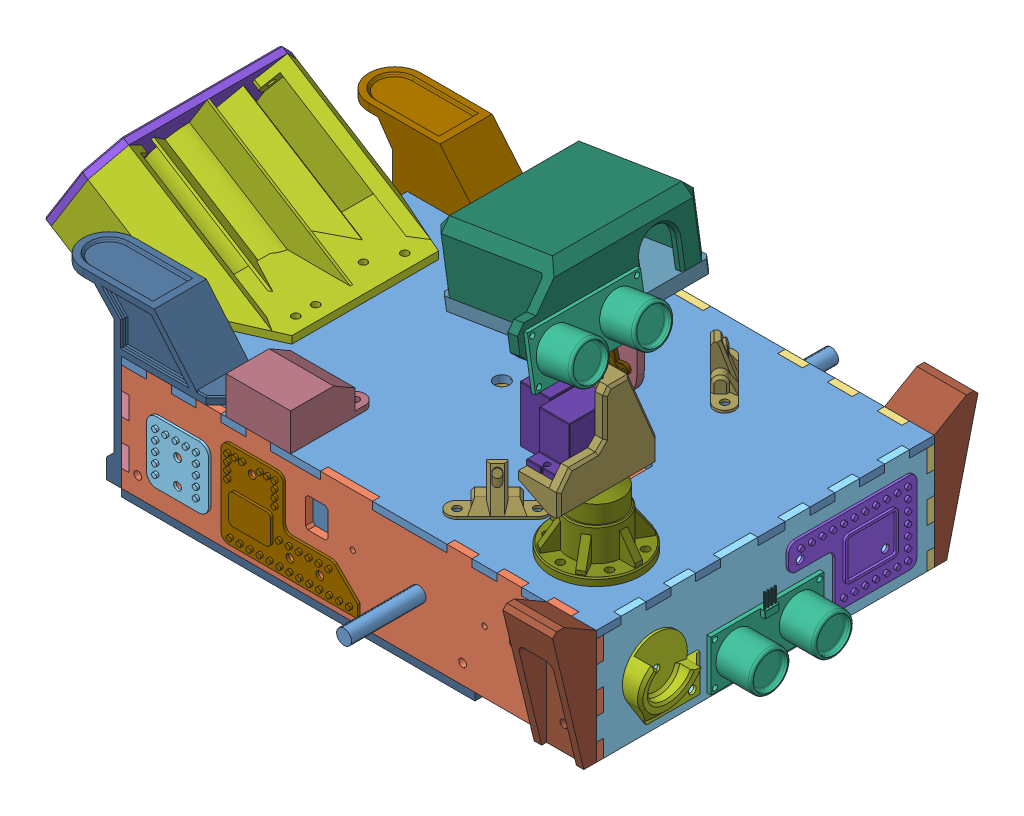
SolidWorks assembly bodySub-2, configuration Default. Lengths in mm.
Overall size (271.51 168.8 196).
99 component instances, 36 part files, 106 mates.
Components (placement in the parent):
- body-top-1: body-top [Default] at (-43.052 0 151.6865) x (1 0 0) z (0 1 0) size (191 136 3)
- body-right-1: body-right [Default] at (-43.052 -43 148.6865) size (191 46 3)
- body-left-1: body-left [Default] at (-43.052 -43 18.6865) x (-1 0 0) z (0 0 -1) size (191 46 3)
- body-rear-1: body-rear [Default] at (-43.052 -43 15.6865) x (0 0 -1) z (1 0 0) size (136 46 3)
- body-front-1: body-front [Default] at (147.948 -43 15.6865) x (0 0 1) z (-1 0 0) size (136 46 3)
- usSensor-1: usSensor [Default] at (-46.052 -45.75 62.8045) x (0 0 1) z (0 -1 0) size (45.5 15.6 26.2)
- usSensor-2: usSensor [Default] at (147.948 -20.8 61.6865) x (0 0 1) z (0 1 0) size (45.5 15.6 26.2)
- power-1: power [Default] at (-43.052 -43 151.6865) x (0 0 1) z (-1 0 0) size (84 85.03 90.67)
- powerCap-1: powerCap [Default] at (-74.8205 44.2822 15.6865) x (0 0 -1) z (-0.848048 0.529919 0) size (84 51.88 5)
- powerShoulder-left-1: powerShoulder-left [Default] at (-43.052 -43 15.6865) x (-1 0 0) z (0 0 -1) size (66.06 69 21)
- powerShoulder-right-1: powerShoulder-right [Default] at (-43.052 -43 109.6865) x (-1 0 0) z (0 0 -1) size (66.06 69 21)
- shoulder-1: shoulder [Default] at (127.948 -43 151.6865) size (20 53.5 17.6)
- shoulder-2: shoulder [Default] at (147.948 -43 15.6865) x (-1 0 0) z (0 0 -1) size (20 53.5 17.6)
- headSub-1: headSub [Default] at (131.8571 34.2972 110.6077) size (71.35 113.8 76.5) (flexible)
  - headServoMount-1: headServoMount [Default] at (-5.7591 24.2018 7.3288) x (0 0 1) z (1 0 0) size (39.75 36.12 28.6)
  - headMount-1: headMount [Default] at (-19.6139 25.1697 -5.5142) x (0.16009 -0.987102 0) z (0 0 -1) size (40 30 34)
  - headBaseplate-1: headBaseplate [Default] at (-50.728 44.8869 -23.5142) x (0 0 1) z (-0.987102 -0.16009 0) size (60 5 50)
  - headCanopy-1: headCanopy [Default] at (-6.1756 82.5045 -23.5142) x (0 0 1) z (0.16009 -0.987102 0) size (76.5 50 25)
  - usSensor-2: usSensor [Default] at (-0.5404 47.7585 50.4858) x (0 0 -1) z (0.16009 -0.987102 0) size (45.5 15.6 26.2)
  - mastMount-top-1: mastMount-top [Default] at (-11.9091 -31.2972 13.0788) size (36 28 36)
  - sg90Servo-1: sg90Servo [Default] at (-5.7591 24.0708 7.3288) x (0 0 1) z (1 0 0) size (32.7 29.37 12.3)
  - sg90Servo-2: sg90Servo [Default] at (-18.0591 24.5458 25.4538) x (0 -1 0) z (1 0 0) size (32.7 29.37 12.3)
  - sg90ServoHorn-star-1: sg90ServoHorn-star [Default] at (-27.3265 20.2151 -5.5142) x (0.16009 -0.987102 0) z (-0.987102 -0.16009 0) size (34.4 4 15.7)
  - pan slot head_am-1: pan slot head_am [B18.6.7M - M3 x 0.5 x 16 Slotted PHMS --16C] at (-20.6532 43.3822 5.4858) x (-0.16009 0.987102 0) z (0.259371 0.042065 -0.964861) size (18.4 5.6 5.6)
  - flat washer narrow_am-1: flat washer narrow_am [B18.22M - Plain washer, 3 mm, narrow] at (-22.6063 55.4248 5.4858) x (-0.16009 0.987102 0) z (-0.259371 -0.042065 0.964861) size (0.9 7 7)
  - flat washer narrow_am-2: flat washer narrow_am [B18.22M - Plain washer, 3 mm, narrow] at (-21.1815 46.6396 5.4858) x (-0.16009 0.987102 0) z (-0.259371 -0.042065 0.964861) size (0.9 7 7)
  - hex nut style 1_am-1: hex nut style 1_am [B18.2.4.1M - Hex nut, Style 1,  M3 x 0.5 --D-C] at (-22.9905 57.7939 5.4858) x (-0.259371 -0.042065 0.964861) z (-0.16009 0.987102 0) size (5.5 6.35 2.4)
  - pan slot head_am-2: pan slot head_am [B18.6.7M - M3 x 0.5 x 16 Slotted PHMS --16C] at (-20.6532 43.3822 18.4858) x (-0.16009 0.987102 0) z (0.259371 0.042065 -0.964861) size (18.4 5.6 5.6)
  - flat washer narrow_am-3: flat washer narrow_am [B18.22M - Plain washer, 3 mm, narrow] at (-22.6063 55.4248 18.4858) x (-0.16009 0.987102 0) z (-0.259371 -0.042065 0.964861) size (0.9 7 7)
  - flat washer narrow_am-4: flat washer narrow_am [B18.22M - Plain washer, 3 mm, narrow] at (-21.1815 46.6396 18.4858) x (-0.16009 0.987102 0) z (-0.259371 -0.042065 0.964861) size (0.9 7 7)
  - hex nut style 1_am-2: hex nut style 1_am [B18.2.4.1M - Hex nut, Style 1,  M3 x 0.5 --D-C] at (-22.9905 57.7939 18.4858) x (-0.259371 -0.042065 0.964861) z (-0.16009 0.987102 0) size (5.5 6.35 2.4)
  - pan slot head_am-3: pan slot head_am [B18.6.7M - M3 x 0.5 x 16 Slotted PHMS --16C] at (-31.4492 41.6313 18.4858) x (-0.16009 0.987102 0) z (0.259371 0.042065 -0.964861) size (18.4 5.6 5.6)
  - flat washer narrow_am-5: flat washer narrow_am [B18.22M - Plain washer, 3 mm, narrow] at (-33.4023 53.6739 18.4858) x (-0.16009 0.987102 0) z (-0.259371 -0.042065 0.964861) size (0.9 7 7)
  - flat washer narrow_am-6: flat washer narrow_am [B18.22M - Plain washer, 3 mm, narrow] at (-31.9775 44.8887 18.4858) x (-0.16009 0.987102 0) z (-0.259371 -0.042065 0.964861) size (0.9 7 7)
  - hex nut style 1_am-3: hex nut style 1_am [B18.2.4.1M - Hex nut, Style 1,  M3 x 0.5 --D-C] at (-33.7865 56.043 18.4858) x (-0.259371 -0.042065 0.964861) z (-0.16009 0.987102 0) size (5.5 6.35 2.4)
  - pan slot head_am-4: pan slot head_am [B18.6.7M - M3 x 0.5 x 16 Slotted PHMS --16C] at (-31.4492 41.6313 5.4858) x (-0.16009 0.987102 0) z (0.259371 0.042065 -0.964861) size (18.4 5.6 5.6)
  - flat washer narrow_am-7: flat washer narrow_am [B18.22M - Plain washer, 3 mm, narrow] at (-33.4023 53.6739 5.4858) x (-0.16009 0.987102 0) z (-0.259371 -0.042065 0.964861) size (0.9 7 7)
  - flat washer narrow_am-8: flat washer narrow_am [B18.22M - Plain washer, 3 mm, narrow] at (-31.9775 44.8887 5.4858) x (-0.16009 0.987102 0) z (-0.259371 -0.042065 0.964861) size (0.9 7 7)
  - hex nut style 1_am-4: hex nut style 1_am [B18.2.4.1M - Hex nut, Style 1,  M3 x 0.5 --D-C] at (-33.7865 56.043 5.4858) x (-0.259371 -0.042065 0.964861) z (-0.16009 0.987102 0) size (5.5 6.35 2.4)
  - pan slot head_am-5: pan slot head_am [B18.6.7M - M2 x 0.4 x 16 Slotted PHMS --16C] at (-24.2091 -0.9542 -2.2712) x (0 0 1) z (-0.877694 -0.479221 0) size (17.6 4 4)
  - flat washer narrow_am-9: flat washer narrow_am [B18.22M - Plain washer, 2 mm, narrow] at (-24.2091 -0.9542 0.2288) x (0 0 1) z (-0.877694 -0.479221 0) size (0.9 5 5)
  - flat washer narrow_am-10: flat washer narrow_am [B18.22M - Plain washer, 2 mm, narrow] at (-24.2091 -0.9542 10.7288) x (0 0 1) z (-0.877694 -0.479221 0) size (0.9 5 5)
  - hex nut style 1_am-5: hex nut style 1_am [B18.2.4.1M - Hex nut, Style 1,  M2 x 0.4 --D-C] at (-24.2091 -0.9542 12.3288) x (0.877694 0.479221 0) z (0 0 1) size (4 4.62 1.6)
  - pan slot head_am-7: pan slot head_am [B18.6.7M - M2 x 0.4 x 10 Slotted PHMS --10C] at (-24.2091 27.3458 4.8288) x (0 0 1) z (-0.99854 -0.054009 0) size (11.6 4 4)
  - flat washer narrow_am-13: flat washer narrow_am [B18.22M - Plain washer, 2 mm, narrow] at (-24.2091 27.3458 7.3288) x (0 0 1) z (-0.99854 -0.054009 0) size (0.9 5 5)
  - flat washer narrow_am-14: flat washer narrow_am [B18.22M - Plain washer, 2 mm, narrow] at (-24.2091 27.3458 13.7288) x (0 0 1) z (-0.99854 -0.054009 0) size (0.9 5 5)
  - hex nut style 1_am-7: hex nut style 1_am [B18.2.4.1M - Hex nut, Style 1,  M2 x 0.4 --D-C] at (-24.2091 27.3458 15.3288) x (0.99854 0.054009 0) z (0 0 1) size (4 4.62 1.6)
  - pan slot head_am-8: pan slot head_am [B18.6.7M - M2 x 0.4 x 10 Slotted PHMS --10C] at (-11.9091 10.9458 32.8288) x (0 -1 0) z (-0.98388 0 -0.178829) size (11.6 4 4)
  - flat washer narrow_am-15: flat washer narrow_am [B18.22M - Plain washer, 2 mm, narrow] at (-11.9091 8.4458 32.8288) x (0 -1 0) z (-0.98388 0 -0.178829) size (0.9 5 5)
  - flat washer narrow_am-16: flat washer narrow_am [B18.22M - Plain washer, 2 mm, narrow] at (-11.9091 2.0458 32.8288) x (0 -1 0) z (-0.98388 0 -0.178829) size (0.9 5 5)
  - hex nut style 1_am-8: hex nut style 1_am [B18.2.4.1M - Hex nut, Style 1,  M2 x 0.4 --D-C] at (-11.9091 0.4458 32.8288) x (0.98388 0 0.178829) z (0 -1 0) size (4 4.62 1.6)
  - pan slot head_am-9: pan slot head_am [B18.6.7M - M2 x 0.4 x 16 Slotted PHMS --16C] at (-11.9091 -5.6542 4.5288) x (0 1 0) z (-0.921484 0 -0.388417) size (17.6 4 4)
  - flat washer narrow_am-17: flat washer narrow_am [B18.22M - Plain washer, 2 mm, narrow] at (-11.9091 -3.1542 4.5288) x (0 1 0) z (-0.921484 0 -0.388417) size (0.9 5 5)
  - flat washer narrow_am-18: flat washer narrow_am [B18.22M - Plain washer, 2 mm, narrow] at (-11.9091 9.3458 4.5288) x (0 1 0) z (-0.970412 0 0.241457) size (0.9 5 5)
  - hex nut style 1_am-9: hex nut style 1_am [B18.2.4.1M - Hex nut, Style 1,  M2 x 0.4 --D-C] at (-11.9091 10.9458 4.5288) x (0.921484 0 0.388417) z (0 1 0) size (4 4.62 1.6)
  - flat washer narrow_am-19: flat washer narrow_am [B18.22M - Plain washer, 2 mm, narrow] at (-26.6104 33.6024 -4.0542) x (0 0 -1) z (0.283495 -0.958974 0) size (0.9 5 5)
  - flat washer narrow_am-20: flat washer narrow_am [B18.22M - Plain washer, 2 mm, narrow] at (-26.6104 33.6024 -10.4142) x (0 0 -1) z (0.283495 -0.958974 0) size (0.9 5 5)
  - hex nut style 1_am-10: hex nut style 1_am [B18.2.4.1M - Hex nut, Style 1,  M2 x 0.4 --D-C] at (-26.6104 33.6024 -12.0142) x (-0.283495 0.958974 0) z (0 0 -1) size (4 4.62 1.6)
  - pan slot head_am-10: pan slot head_am [B18.6.7M - M2 x 0.4 x 10 Slotted PHMS --10C] at (-26.6104 33.6024 -1.5542) x (0 0 -1) z (0.283495 -0.958974 0) size (11.6 4 4)
  - flat washer narrow_am-21: flat washer narrow_am [B18.22M - Plain washer, 2 mm, narrow] at (-18.1877 19.7724 -4.0542) x (0 0 -1) z (0.283495 -0.958974 0) size (0.9 5 5)
  - flat washer narrow_am-22: flat washer narrow_am [B18.22M - Plain washer, 2 mm, narrow] at (-18.1877 19.7724 -10.4142) x (0 0 -1) z (0.283495 -0.958974 0) size (0.9 5 5)
  - hex nut style 1_am-11: hex nut style 1_am [B18.2.4.1M - Hex nut, Style 1,  M2 x 0.4 --D-C] at (-18.1877 19.7724 -12.0142) x (-0.283495 0.958974 0) z (0 0 -1) size (4 4.62 1.6)
  - pan slot head_am-11: pan slot head_am [B18.6.7M - M2 x 0.4 x 10 Slotted PHMS --10C] at (-18.1877 19.7724 -1.5542) x (0 0 -1) z (0.283495 -0.958974 0) size (11.6 4 4)
  - flat washer narrow_am-23: flat washer narrow_am [B18.22M - Plain washer, 2 mm, narrow] at (-23.1685 12.3797 -4.0542) x (0 0 -1) z (0.283495 -0.958974 0) size (0.9 5 5)
  - flat washer narrow_am-24: flat washer narrow_am [B18.22M - Plain washer, 2 mm, narrow] at (-23.1685 12.3797 -10.4142) x (0 0 -1) z (0.283495 -0.958974 0) size (0.9 5 5)
  - hex nut style 1_am-12: hex nut style 1_am [B18.2.4.1M - Hex nut, Style 1,  M2 x 0.4 --D-C] at (-23.1685 12.3797 -12.0142) x (-0.283495 0.958974 0) z (0 0 -1) size (4 4.62 1.6)
  - pan slot head_am-12: pan slot head_am [B18.6.7M - M2 x 0.4 x 10 Slotted PHMS --10C] at (-23.1685 12.3797 -1.5542) x (0 0 -1) z (0.283495 -0.958974 0) size (11.6 4 4)
  - flat washer narrow_am-25: flat washer narrow_am [B18.22M - Plain washer, 2 mm, narrow] at (-30.2304 17.8193 -4.0542) x (0 0 -1) z (0.283495 -0.958974 0) size (0.9 5 5)
  - flat washer narrow_am-26: flat washer narrow_am [B18.22M - Plain washer, 2 mm, narrow] at (-30.2304 17.8193 -10.4142) x (0 0 -1) z (0.283495 -0.958974 0) size (0.9 5 5)
  - hex nut style 1_am-13: hex nut style 1_am [B18.2.4.1M - Hex nut, Style 1,  M2 x 0.4 --D-C] at (-30.2304 17.8193 -12.0142) x (-0.283495 0.958974 0) z (0 0 -1) size (4 4.62 1.6)
  - pan slot head_am-13: pan slot head_am [B18.6.7M - M2 x 0.4 x 10 Slotted PHMS --10C] at (-30.2304 17.8193 -1.5542) x (0 0 -1) z (0.283495 -0.958974 0) size (11.6 4 4)
  - flat washer narrow_am-27: flat washer narrow_am [B18.22M - Plain washer, 2 mm, narrow] at (-1.9228 66.276 6.6858) x (-0.987102 -0.16009 0) z (0.068011 -0.419347 0.905275) size (0.9 5 5)
  - flat washer narrow_am-28: flat washer narrow_am [B18.22M - Plain washer, 2 mm, narrow] at (-7.3518 65.3955 6.6858) x (-0.987102 -0.16009 0) z (0.068011 -0.419347 0.905275) size (0.9 5 5)
  - hex nut style 1_am-14: hex nut style 1_am [B18.2.4.1M - Hex nut, Style 1,  M2 x 0.4 --D-C] at (-8.9312 65.1394 6.6858) x (-0.068011 0.419347 -0.905275) z (-0.987102 -0.16009 0) size (4 4.62 1.6)
  - pan slot head_am-14: pan slot head_am [B18.6.7M - M2 x 0.4 x 10 Slotted PHMS --10C] at (0.545 66.6763 6.6858) x (-0.987102 -0.16009 0) z (0.068011 -0.419347 0.905275) size (11.6 4 4)
  - flat washer narrow_am-29: flat washer narrow_am [B18.22M - Plain washer, 2 mm, narrow] at (-1.9228 66.276 48.7858) x (-0.987102 -0.16009 0) z (0.068011 -0.419347 0.905275) size (0.9 5 5)
  - flat washer narrow_am-30: flat washer narrow_am [B18.22M - Plain washer, 2 mm, narrow] at (-8.3389 65.2354 48.7858) x (-0.987102 -0.16009 0) z (0.068011 -0.419347 0.905275) size (0.9 5 5)
  - hex nut style 1_am-15: hex nut style 1_am [B18.2.4.1M - Hex nut, Style 1,  M2 x 0.4 --D-C] at (-9.9183 64.9793 48.7858) x (-0.068011 0.419347 -0.905275) z (-0.987102 -0.16009 0) size (4 4.62 1.6)
  - pan slot head_am-15: pan slot head_am [B18.6.7M - M2 x 0.4 x 10 Slotted PHMS --10C] at (0.545 66.6763 48.7858) x (-0.987102 -0.16009 0) z (0.068011 -0.419347 0.905275) size (11.6 4 4)
- pivotAxle-1: pivotAxle [Default] at (76.448 -20 181.6865) x (-0.972905 0.231206 0) z (-0.231206 -0.972905 0) size (6 196 6)
- edison-arduino-1: edison-arduino [Default] at (-30.752 -13.38 66.6865) x (1 0 0) z (0 0 -1) size (127.2 12.67 72)
- diffMount-mid-1: diffMount-mid [Default] at (-43.052 0 151.6865) x (-1 0 0) z (0 -1 0) size (30 30 3)
- diffMount-bottom-1: diffMount-bottom [Default] at (-43.052 -3 151.6865) x (-1 0 0) z (0 -1 0) size (30 30 3)
- sideDetailA-left-1: sideDetailA-left [Default] at (-43.052 -43 15.6865) x (-1 0 0) z (0 0 -1) size (25 25 2)
- sideDetailB-1: sideDetailB [Default] at (-43.052 -43 15.6865) x (-1 0 0) z (0 0 -1) size (55 35 2)
- fontDetailA-1: fontDetailA [Default] at (147.948 -43 15.6865) x (0 0 -1) z (1 0 0) size (30.16 30.17 9.09)
- frontDetailB-1: frontDetailB [Default] at (147.948 -43 15.6865) x (0 0 -1) z (1 0 0) size (51.58 33 2)
- sideDetailB-mirr-1: sideDetailB-mirr [Default] at (-43.052 -43 151.6865) x (-1 0 0) z (0 0 -1) size (55 35 2)
- sideDetailA-left-2: sideDetailA-left [Default] at (3.948 -43 151.6865) size (25 25 2)
- bodyUnderCover-1: bodyUnderCover [Default] at (99.148 -43 15.6865) x (1 0 0) z (0 -1 0) size (142.2 136 9)
- underCoverMagnetMount-front-1: underCoverMagnetMount-front [Default] at (99.148 -43 15.6865) x (-1 0 0) z (0 1 0) size (7 7 11.3)
- underCoverMagnetMount-front-2: underCoverMagnetMount-front [Default] at (89.148 -43 151.6865) x (1 0 0) z (0 1 0) size (7 7 11.3)
- underCoverMagnetMount-front-3: underCoverMagnetMount-front [Default] at (-31.552 -43 15.6865) x (-1 0 0) z (0 1 0) size (7 7 11.3)
- underCoverMagnetMount-front-4: underCoverMagnetMount-front [Default] at (-41.552 -43 151.6865) x (1 0 0) z (0 1 0) size (7 7 11.3)
- topDetailA-1: topDetailA [Default] at (-43.052 3 151.6865) x (1 0 0) z (0 1 0) size (24.26 24.26 16)
- topDetailA-2: topDetailA [Default] at (108.7154 3 168.7548) x (0 0 -1) z (0 1 0) size (24.26 24.26 16)
- topDetailB-1: topDetailB [Default] at (-45.052 3 151.6865) x (1 0 0) z (0 1 0) size (26 34 15)
- topDetailCA-1: topDetailCA [Default] at (-46.5393 3 149.9052) x (1 0 0) z (0 1 0) size (20.56 18.54 22.66)
- topDetailCB-1: topDetailCB [Default] at (1.7026 61.1918 61.409) x (0.910046 -0.22774 0.34634) z (0.414508 0.5 -0.760384) size (46.65 24.53 4)
Mates (geometry in assembly coordinates):
- Coincident23: coincident anti-aligned: plane of body-front-1 through (147.948 -43 15.6865) normal (1 0 0); plane of usSensor-2 through (147.948 -20.8 61.6865) normal (-1 0 0)
- Coincident22: coincident anti-aligned: plane of body-top-1 through (144.948 -0.001 141.6865) normal (1 0 0); plane of body-front-1 through (144.948 -43 15.6865) normal (-1 0 0)
- Coincident21: coincident anti-aligned: plane of body-top-1 through (147.948 -0.001 141.6865) normal (0 0 -1); plane of body-front-1 through (147.949 -43 141.6865) normal (0 0 1)
- Coincident17: coincident anti-aligned: plane of body-top-1 through (-40.052 -0.001 35.6865) normal (-1 0 0); plane of body-rear-1 through (-40.052 -43 15.6865) normal (1 0 0)
- Coincident16: coincident anti-aligned: plane of body-top-1 through (-43.052 -0.001 25.6865) normal (0 0 1); plane of body-rear-1 through (-43.053 -43 25.6865) normal (0 0 -1)
- Coincident12: coincident anti-aligned: plane of body-top-1 through (-43.052 -0.001 18.6865) normal (0 0 -1); plane of body-left-1 through (-43.052 -43 18.6865) normal (0 0 1)
- Coincident11: coincident anti-aligned: plane of body-top-1 through (137.948 -0.001 15.6865) normal (-1 0 0); plane of body-left-1 through (137.948 3 15.6855) normal (1 0 0)
- Coincident7: coincident anti-aligned: plane of body-top-1 through (-43.052 -0.001 148.6865) normal (0 0 1); plane of body-right-1 through (-43.052 -43 148.6865) normal (0 0 -1)
- Coincident6: coincident anti-aligned: plane of body-top-1 through (-33.052 -0.001 151.6865) normal (1 0 0); plane of body-right-1 through (-33.052 0 151.6875) normal (-1 0 0)
- Coincident2: coincident anti-aligned: plane of body-top-1 through (-43.052 0 151.6865) normal (0 -1 0); plane of assembly through (0 0 0) normal (0 1 0)
- Coincident24: coincident anti-aligned: plane of power-1 through (-46.052 -43 151.6865) normal (-1 0 0); plane of usSensor-1 through (-46.052 -45.75 62.8045) normal (1 0 0)
- Concentric5: concentric anti-aligned: cylinder of body-top-1 through (-19.052 3 105.6173) axis (0 -1 0) radius 1.55; cylinder of power-1 through (-19.052 -43.001 105.6173) axis (0 1 0) radius 1.55
- Coincident25: coincident anti-aligned: plane of body-top-1 through (-43.052 3 151.6865) normal (0 1 0); plane of power-1 through (-13.052 3 151.6865) normal (0 -1 0)
- Concentric8: concentric aligned: cylinder of body-rear-1 through (-40.052 -27.05 63.6865) axis (-1 0 0) radius 1.05; cylinder of power-1 through (-40.0822 -27.05 63.6865) axis (-1 0 0) radius 1.05
- Coincident26: coincident anti-aligned: plane of power-1 through (-105.1238 -4.2132 151.6865) normal (-0.848048 0.529919 0); plane of powerCap-1 through (-74.8205 44.2822 15.6865) normal (0.848048 -0.529919 0)
- Concentric11: concentric anti-aligned: cylinder of powerCap-1 through (-83.4594 36.1202 56.0789) axis (0.848048 -0.529919 0) radius 1.55; cylinder of power-1 through (2.7341 -17.7395 56.0789) axis (-0.848048 0.529919 0) radius 1.55
- Concentric12: concentric anti-aligned: cylinder of power-1 through (2.7341 -17.7395 111.2941) axis (-0.848048 0.529919 0) radius 1.55; cylinder of powerCap-1 through (-83.4594 36.1202 111.2941) axis (0.848048 -0.529919 0) radius 1.55
- Coincident27: coincident anti-aligned: plane of body-rear-1 through (-43.052 -43 15.6865) normal (-1 0 0); plane of powerShoulder-right-1 through (-43.052 -43 151.6865) normal (1 0 0)
- Coincident28: coincident anti-aligned: plane of body-top-1 through (-43.052 3 151.6865) normal (0 1 0); plane of powerShoulder-right-1 through (-43.052 3 81.1263) normal (0 -1 0)
- Concentric13: concentric anti-aligned: cylinder of body-top-1 through (-8.052 3 135.6865) axis (0 -1 0) radius 1.55; cylinder of powerShoulder-right-1 through (-8.052 -43.001 135.6865) axis (0 1 0) radius 1.55
- Coincident29: coincident anti-aligned: plane of body-rear-1 through (-43.052 -43 15.6865) normal (-1 0 0); plane of powerShoulder-left-1 through (-43.052 -43 15.6865) normal (1 0 0)
- Coincident30: coincident anti-aligned: plane of body-top-1 through (-43.052 3 151.6865) normal (0 1 0); plane of powerShoulder-left-1 through (-43.052 3 86.2467) normal (0 -1 0)
- Concentric14: concentric anti-aligned: cylinder of body-top-1 through (-8.052 3 31.6865) axis (0 -1 0) radius 1.55; cylinder of powerShoulder-left-1 through (-8.052 -43.001 31.6865) axis (0 1 0) radius 1.55
- Coincident31: coincident anti-aligned: plane of body-left-1 through (-43.052 -43 15.6865) normal (0 0 -1); plane of shoulder-2 through (127.948 -43 15.6865) normal (0 0 1)
- Concentric15: concentric anti-aligned: cylinder of body-left-1 through (137.948 -13 15.6865) axis (0 0 1) radius 1.55; cylinder of shoulder-2 through (137.948 -13 12.6865) axis (0 0 -1) radius 1.55
- Concentric16: concentric anti-aligned: cylinder of body-left-1 through (137.948 -33 15.6865) axis (0 0 1) radius 1.55; cylinder of shoulder-2 through (137.948 -33 12.6865) axis (0 0 -1) radius 1.55
- Coincident32: coincident anti-aligned: plane of body-right-1 through (-43.052 -43 151.6865) normal (0 0 1); plane of shoulder-1 through (147.948 -43 151.6865) normal (0 0 -1)
- Concentric17: concentric anti-aligned: cylinder of body-right-1 through (137.948 -13 151.6865) axis (0 0 -1) radius 1.55; cylinder of shoulder-1 through (137.948 -13 154.6865) axis (0 0 1) radius 1.55
- Concentric18: concentric anti-aligned: cylinder of body-right-1 through (137.948 -33 151.6865) axis (0 0 -1) radius 1.55; cylinder of shoulder-1 through (137.948 -33 154.6865) axis (0 0 1) radius 1.55
- Coincident33: coincident anti-aligned: plane of body-top-1 through (-43.052 3 151.6865) normal (0 1 0); plane of headSub-1/mastMount-top-1 through (119.948 3 123.6865) normal (0 -1 0)
- Concentric19: concentric anti-aligned: cylinder of body-top-1 through (132.5054 3 116.4365) axis (0 -1 0) radius 1.55; cylinder of headSub-1/mastMount-top-1 through (132.5054 6 116.4365) axis (0 1 0) radius 1.55
- Concentric20: concentric anti-aligned: cylinder of body-top-1 through (107.3906 3 130.9365) axis (0 -1 0) radius 1.55; cylinder of headSub-1/mastMount-top-1 through (107.3906 6 130.9365) axis (0 1 0) radius 1.55
- Coincident34: coincident aligned: plane of body-top-1 through (-43.052 3 151.6865) normal (0 1 0); plane of body-front-1 through (144.948 3 151.6865) normal (0 1 0)
- Coincident35: coincident aligned: plane of body-top-1 through (-43.052 3 151.6865) normal (0 1 0); plane of body-left-1 through (-43.052 3 15.6865) normal (0 1 0)
- Coincident36: coincident aligned: plane of body-top-1 through (-43.052 3 151.6865) normal (0 1 0); plane of body-rear-1 through (-40.052 3 15.6865) normal (0 1 0)
- Coincident37: coincident aligned: plane of body-top-1 through (-43.052 3 151.6865) normal (0 1 0); plane of body-right-1 through (147.948 3 151.6865) normal (0 1 0)
- Concentric21: concentric anti-aligned: cylinder of body-left-1 through (76.448 -20 18.6875) axis (0 0 -1) radius 3; cylinder of pivotAxle-1 through (76.448 -20 -14.3135) axis (0 0 1) radius 3
- Symmetric2: symmetric aligned: plane of body-top-1 through (-43.052 0 83.6865) normal (0 0 -1); plane of pivotAxle-1 through (76.448 -20 -14.3135) normal (0 0 -1); plane of pivotAxle-1 through (76.448 -20 181.6865) normal (0 0 1)
- Parallel1: parallel anti-aligned: plane of body-top-1 through (-43.052 0 151.6865) normal (0 -1 0); plane of edison-arduino-1 through (-30.752 -13.38 66.6865) normal (0 1 0)
- Parallel2: parallel anti-aligned: plane of body-rear-1 through (-40.052 -43 15.6865) normal (1 0 0); plane of edison-arduino-1 through (-30.752 -15 66.6865) normal (-1 0 0)
- Distance2: distance = 2 mm anti-aligned: plane of edison-arduino-1 through (-30.752 -15 66.6865) normal (0 -1 0); cylinder of pivotAxle-1 through (76.448 -20 -14.3135) axis (0 0 1) radius 3
- Distance3: distance = 1 mm anti-aligned: plane of edison-arduino-1 through (80.448 -26 134.6865) normal (-1 0 0); cylinder of pivotAxle-1 through (76.448 -20 -14.3135) axis (0 0 1) radius 3
- Distance4: distance = 10 mm anti-aligned: plane of edison-arduino-1 through (-30.752 -15 138.6865) normal (0 0 1); plane of body-right-1 through (-43.052 -43 148.6865) normal (0 0 -1)
- InPlace1: in place: plane of body-top-1 through (-43.052 0 151.6865) normal (0 -1 0); plane of ? through (0 0 0) normal (0 -1 0); moOrthogonalPlaneRef_w of body-top-1 through (-43.052 0 151.6865) normal (0 -1 0); unknown of ?; plane of body-top-1 through (-43.052 0 151.6865) normal (0 -1 0); line of ? through (55 -55 0) axis (0 0 -1); plane of body-top-1 through (-43.052 0 151.6865) normal (0 -1 0); unknown of diffMount-mid-1
- Coincident41: coincident aligned: 
- Coincident42: coincident aligned: plane of body-top-1 through (-43.052 0 151.6865) normal (0 0 -1); unknown of diffMount-mid-1
- Coincident43: coincident anti-aligned: plane of body-top-1 through (-43.052 0 151.6865) normal (1 0 0); unknown of diffMount-mid-1
- InPlace2: in place: plane of diffMount-mid-1 through (41.948 -3 83.6865) normal (0 -1 0); plane of ? through (0 -3 0) normal (0 -1 0); plane of diffMount-mid-1 through (41.948 -3 83.6865) normal (0 -1 0); unknown of ?; plane of diffMount-mid-1 through (41.948 -3 83.6865) normal (0 -1 0); line of ? through (-55 0 -3) axis (0 -1 0); plane of diffMount-mid-1 through (41.948 -3 83.6865) normal (0 -1 0); unknown of diffMount-bottom-1
- Coincident44: coincident aligned: 
- Coincident45: coincident aligned: plane of diffMount-mid-1 through (-43.052 -3 151.6865) normal (0 0 -1); unknown of diffMount-bottom-1
- Coincident46: coincident anti-aligned: plane of diffMount-mid-1 through (-43.052 -3 151.6865) normal (1 0 0); unknown of diffMount-bottom-1
- InPlace3: in place: plane of body-left-1 through (-43.052 -43 15.6865) normal (0 0 -1); plane of ? through (0 0 15.6865) normal (0 0 -1); plane of body-left-1 through (-43.052 -43 15.6865) normal (0 0 -1); unknown of ?; plane of body-left-1 through (-43.052 -43 15.6865) normal (0 0 -1); plane of ? through (0 0 15.6865) normal (-1 0 0); plane of body-left-1 through (-43.052 -43 15.6865) normal (0 0 -1); unknown of ?
- Coincident47: coincident aligned: 
- Coincident48: coincident aligned: plane of body-left-1 through (-43.052 -43 15.6865) normal (0 1 0); unknown of ?
- Coincident49: coincident anti-aligned: plane of body-left-1 through (-43.052 -43 15.6865) normal (1 0 0); plane of ? through (-43.052 -43 15.6865) normal (-1 0 0)
- InPlace4: in place: plane of body-left-1 through (-43.052 -43 15.6865) normal (0 0 -1); plane of ? through (0 0 15.6865) normal (0 0 -1); plane of body-left-1 through (-43.052 -43 15.6865) normal (0 0 -1); unknown of ?; plane of body-left-1 through (-43.052 -43 15.6865) normal (0 0 -1); plane of ? through (0 0 15.6865) normal (-1 0 0); plane of body-left-1 through (-43.052 -43 15.6865) normal (0 0 -1); unknown of ?
- Coincident50: coincident aligned: 
- Coincident51: coincident aligned: plane of body-left-1 through (-43.052 -43 15.6865) normal (0 1 0); unknown of ?
- Coincident52: coincident anti-aligned: plane of body-left-1 through (-43.052 -43 15.6865) normal (1 0 0); plane of ? through (-43.052 -43 15.6865) normal (-1 0 0)
- InPlace5: in place: plane of body-front-1 through (147.948 -43 15.6865) normal (1 0 0); plane of ? through (147.948 0 0) normal (1 0 0); plane of body-front-1 through (147.948 -43 15.6865) normal (1 0 0); line of ? through (-55 147.948 0) axis (0 0 1); plane of body-front-1 through (147.948 -43 15.6865) normal (1 0 0); plane of ? through (147.948 0 0) normal (0 0 -1); plane of body-front-1 through (147.948 -43 15.6865) normal (1 0 0); unknown of ?
- Coincident53: coincident aligned: 
- Coincident54: coincident aligned: plane of body-front-1 through (147.948 -43 15.6865) normal (0 1 0); line of ? through (-43 15.6865 0) axis (1 0 0)
- Coincident55: coincident anti-aligned: plane of body-front-1 through (147.948 -43 15.6865) normal (0 0 1); plane of ? through (147.948 -43 15.6865) normal (0 0 -1)
- InPlace6: in place: plane of body-front-1 through (147.948 -43 15.6865) normal (1 0 0); plane of ? through (147.948 0 0) normal (1 0 0); plane of body-front-1 through (147.948 -43 15.6865) normal (1 0 0); line of ? through (-55 147.948 0) axis (0 0 1); plane of body-front-1 through (147.948 -43 15.6865) normal (1 0 0); plane of ? through (147.948 0 0) normal (0 0 -1); plane of body-front-1 through (147.948 -43 15.6865) normal (1 0 0); unknown of ?
- Coincident56: coincident aligned: 
- Coincident57: coincident aligned: plane of body-front-1 through (147.948 -43 15.6865) normal (0 1 0); line of ? through (-43 15.6865 0) axis (1 0 0)
- Coincident58: coincident anti-aligned: plane of body-front-1 through (147.948 -43 15.6865) normal (0 0 1); plane of ? through (147.948 -43 15.6865) normal (0 0 -1)
- Coincident59: coincident anti-aligned: plane of body-right-1 through (-43.052 -43 151.6865) normal (0 0 1); plane of sideDetailB-mirr-1 through (-43.052 -43 151.6865) normal (0 0 -1)
- Concentric22: concentric aligned: cylinder of body-right-1 through (10.448 -11 148.6855) axis (0 0 1) radius 1.55; cylinder of sideDetailB-mirr-1 through (10.448 -11 151.6855) axis (0 0 1) radius 1.55
- Concentric23: concentric aligned: cylinder of body-right-1 through (37.7054 -32.5 148.6855) axis (0 0 1) radius 1.55; cylinder of sideDetailB-mirr-1 through (37.7054 -32.5 151.6855) axis (0 0 1) radius 1.55
- Concentric24: concentric aligned: cylinder of body-right-1 through (-19.552 -20 148.6855) axis (0 0 1) radius 1.55; cylinder of sideDetailA-left-2 through (-19.552 -20 151.6855) axis (0 0 1) radius 1.55
- Concentric25: concentric aligned: cylinder of body-right-1 through (-19.552 -30 148.6855) axis (0 0 1) radius 1.55; cylinder of sideDetailA-left-2 through (-19.552 -30 151.6855) axis (0 0 1) radius 1.55
- Coincident60: coincident anti-aligned: plane of body-right-1 through (-43.052 -43 151.6865) normal (0 0 1); plane of sideDetailA-left-2 through (3.948 -43 151.6865) normal (0 0 -1)
- Coincident62: coincident aligned: plane of body-rear-1 through (-43.052 -43 15.6865) normal (-1 0 0); plane of bodyUnderCover-1 through (-43.052 -49 15.6865) normal (-1 0 0)
- Coincident64: coincident aligned: plane of body-left-1 through (-43.052 -43 15.6865) normal (0 0 -1); plane of bodyUnderCover-1 through (99.148 -49 15.6865) normal (0 0 -1)
- Coincident65: coincident anti-aligned: plane of body-left-1 through (147.948 -43 15.6865) normal (0 -1 0); plane of bodyUnderCover-1 through (99.148 -43 15.6865) normal (0 1 0)
- InPlace7: in place: plane of bodyUnderCover-1 through (99.148 -43 15.6865) normal (0 1 0); plane of ? through (0 -43 0) normal (0 1 0); plane of bodyUnderCover-1 through (99.148 -43 15.6865) normal (0 1 0); plane of ? through (0 -43 0) normal (0 0 -1); plane of bodyUnderCover-1 through (99.148 -43 15.6865) normal (0 1 0); line of ? through (-55 0 -43) axis (0 1 0); plane of bodyUnderCover-1 through (99.148 -43 15.6865) normal (0 1 0); unknown of underCoverMagnetMount-front-1
- Coincident66: coincident aligned: 
- Coincident67: coincident aligned: plane of bodyUnderCover-1 through (99.148 -43 15.6865) normal (0 0 1); unknown of underCoverMagnetMount-front-1
- Coincident68: coincident anti-aligned: plane of bodyUnderCover-1 through (99.148 -43 15.6865) normal (1 0 0); unknown of underCoverMagnetMount-front-1
- Coincident69: coincident anti-aligned: plane of body-right-1 through (-43.052 -43 148.6865) normal (0 0 -1); plane of underCoverMagnetMount-front-2 through (89.148 -40.7 148.6865) normal (0 0 1)
- Concentric27: concentric anti-aligned: cylinder of bodyUnderCover-1 through (94.148 -45.3 145.1865) axis (0 1 0) radius 1.55; cylinder of underCoverMagnetMount-front-2 through (94.148 -40.7 145.1865) axis (0 -1 0) radius 1.55
- Coincident70: coincident anti-aligned: plane of bodyUnderCover-1 through (99.148 -43 15.6865) normal (0 1 0); plane of underCoverMagnetMount-front-2 through (89.148 -43 151.6865) normal (0 -1 0)
- Coincident71: coincident anti-aligned: plane of body-left-1 through (-43.052 -43 18.6865) normal (0 0 1); plane of underCoverMagnetMount-front-3 through (-31.552 -40.7 18.6865) normal (0 0 -1)
- Concentric28: concentric anti-aligned: cylinder of bodyUnderCover-1 through (-36.552 -45.3 22.1865) axis (0 1 0) radius 1.55; cylinder of underCoverMagnetMount-front-3 through (-36.552 -40.7 22.1865) axis (0 -1 0) radius 1.55
- Coincident72: coincident anti-aligned: plane of bodyUnderCover-1 through (99.148 -43 15.6865) normal (0 1 0); plane of underCoverMagnetMount-front-3 through (-31.552 -43 15.6865) normal (0 -1 0)
- Coincident73: coincident anti-aligned: plane of body-right-1 through (-43.052 -43 148.6865) normal (0 0 -1); plane of underCoverMagnetMount-front-4 through (-41.552 -40.7 148.6865) normal (0 0 1)
- Concentric29: concentric anti-aligned: cylinder of bodyUnderCover-1 through (-36.552 -45.3 145.1865) axis (0 1 0) radius 1.55; cylinder of underCoverMagnetMount-front-4 through (-36.552 -40.7 145.1865) axis (0 -1 0) radius 1.55
- Coincident74: coincident anti-aligned: plane of bodyUnderCover-1 through (99.148 -43 15.6865) normal (0 1 0); plane of underCoverMagnetMount-front-4 through (-41.552 -43 151.6865) normal (0 -1 0)
- InPlace8: in place: plane of body-top-1 through (-43.052 3 151.6865) normal (0 1 0); plane of ? through (0 3 0) normal (0 1 0); plane of body-top-1 through (-43.052 3 151.6865) normal (0 1 0); plane of ? through (0 3 0) normal (0 0 -1); plane of body-top-1 through (-43.052 3 151.6865) normal (0 1 0); line of ? through (-55 0 3) axis (0 1 0); plane of body-top-1 through (-43.052 3 151.6865) normal (0 1 0); unknown of topDetailA-1
- Coincident75: coincident aligned: 
- Coincident76: coincident aligned: plane of body-top-1 through (-43.052 3 151.6865) normal (0 0 -1); plane of topDetailA-1 through (-43.052 3 151.6865) normal (0 0 -1)
- Coincident77: coincident anti-aligned: plane of body-top-1 through (-43.052 3 151.6865) normal (-1 0 0); unknown of topDetailA-1
- Coincident78: coincident anti-aligned: plane of body-top-1 through (-43.052 3 151.6865) normal (0 1 0); plane of topDetailA-2 through (108.7154 3 168.7548) normal (0 -1 0)
- Perpendicular1: perpendicular: plane of topDetailA-2 through (95.2501 4 52.9763) normal (-0.707107 0 0.707107); plane of topDetailA-1 through (78.3833 4 143.8781) normal (0.707107 0 0.707107)
- Coincident86: coincident anti-aligned: plane of body-top-1 through (-43.052 3 151.6865) normal (0 1 0); plane of topDetailCA-1 through (-46.5393 3 149.9052) normal (0 -1 0)
- InPlace11: in place: plane of topDetailCA-1 through (22.6249 60.6918 73.8008) normal (0.414508 0.5 -0.760384); plane of ? through (-6.7949 -8.1964 12.4648) normal (0.414508 0.5 -0.760384); plane of topDetailCA-1 through (22.6249 60.6918 73.8008) normal (0.414508 0.5 -0.760384); unknown of ?; plane of topDetailCA-1 through (22.6249 60.6918 73.8008) normal (0.414508 0.5 -0.760384); unknown of ?; plane of topDetailCA-1 through (23.0394 61.1918 73.0404) normal (0.414508 0.5 -0.760384); unknown of topDetailCB-1
- Coincident87: coincident aligned: 
- Coincident88: coincident aligned: plane of topDetailCA-1 through (1.7026 61.1918 61.409) normal (0 -0.835544 -0.549423); unknown of topDetailCB-1
- Coincident89: coincident anti-aligned: plane of topDetailCA-1 through (1.7026 61.1918 61.409) normal (-0.910046 0.22774 -0.34634); unknown of topDetailCB-1
- Coincident87: coincident aligned: plane of body-right-1 through (-43.052 -43 151.6865) normal (0 0 1); plane of topDetailB-1 through (24.948 18 151.6865) normal (0 0 1)
- Coincident88: coincident anti-aligned: plane of body-top-1 through (-43.052 3 151.6865) normal (0 1 0); plane of topDetailB-1 through (-45.052 3 151.6865) normal (0 -1 0)
- Distance5: distance = 2 mm anti-aligned: plane of topDetailB-1 through (-1.052 18 151.6865) normal (-1 0 0); plane of powerShoulder-right-1 through (-3.052 -43 151.6865) normal (1 0 0)
- Distance6: distance = 1 mm anti-aligned: plane of usSensor-1 through (-47.652 -25.55 62.8045) normal (0 1 0); plane of power-1 through (-103.7193 -24.55 106.1865) normal (0 -1 0)
- Distance7: distance = 2 mm aligned: plane of usSensor-2 through (149.548 -41 61.6865) normal (0 -1 0); plane of body-front-1 through (144.948 -43 15.6865) normal (0 -1 0)
- Distance8: distance = 46 mm aligned: plane of usSensor-2 through (149.548 -20.8 61.6865) normal (0 0 -1); plane of body-front-1 through (144.948 3 15.6865) normal (0 0 -1)
